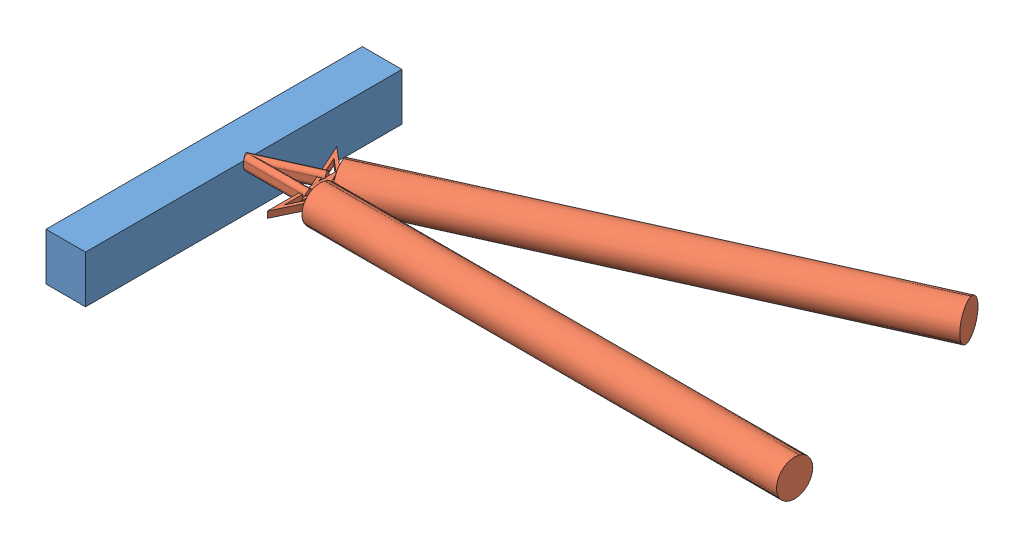
SolidWorks assembly Assem1, configuration Default. Lengths in mm.
Overall size (370.78 39.5 264.55).
3 component instances, 2 part files, 8 mates.
Components (placement in the parent):
- beam-1: beam [Default] at (-24.6038 19.5134 -0.274) size (25 30 200)
- drawing-test-1: drawing-test [Default] at (333.6753 32.5134 -2.7005) x (0 0 1) z (0 -1 0) size (45.11 345.78 23)
- drawing-test-2: drawing-test [Default] at (302.2822 32.5134 -144.255) x (0.409995 0 0.912088) z (0 -1 0) size (45.11 345.78 23)
Mates (geometry in assembly coordinates):
- Parallel1: parallel aligned: plane of beam-1 through (-37.1038 34.5134 -100.274) normal (0 1 0); plane of drawing-test-1 through (333.6753 34.5134 -2.7005) normal (0 1 0)
- Parallel3: parallel aligned: plane of beam-1 through (-37.1038 4.5134 -100.274) normal (0 -1 0); plane of drawing-test-1 through (333.6753 30.5134 -2.7005) normal (0 -1 0)
- Coincident7: coincident aligned: plane of beam-1 through (-37.1038 34.5134 -100.274) normal (0 1 0); plane of drawing-test-1 through (333.6753 34.5134 -2.7005) normal (0 1 0)
- Coincident8: coincident: line of beam-1 through (-12.1038 34.5134 -0.274) axis (0 -1 0); plane of drawing-test-1 through (-12.1038 34.5134 -2.7005) normal (-1 0 0)
- Coincident11: coincident anti-aligned: line of beam-1 through (-12.1038 34.5134 -0.274) axis (0 -1 0); line of drawing-test-1 through (-12.1038 30.5134 -0.274) axis (0 1 0)
- Perpendicular2: perpendicular: plane of beam-1 through (-12.1038 4.5134 -100.274) normal (1 0 0); plane of drawing-test-1 through (26.8962 34.5134 -5.1269) normal (0 0 -1)
- Coincident13: coincident aligned: plane of beam-1 through (-37.1038 34.5134 -100.274) normal (0 1 0); plane of drawing-test-2 through (302.2822 34.5134 -144.255) normal (0 1 0)
- Coincident14: coincident anti-aligned: line of beam-1 through (-12.1038 34.5134 -0.274) axis (0 -1 0); line of drawing-test-2 through (-12.1038 30.5134 -0.274) axis (0 1 0)
